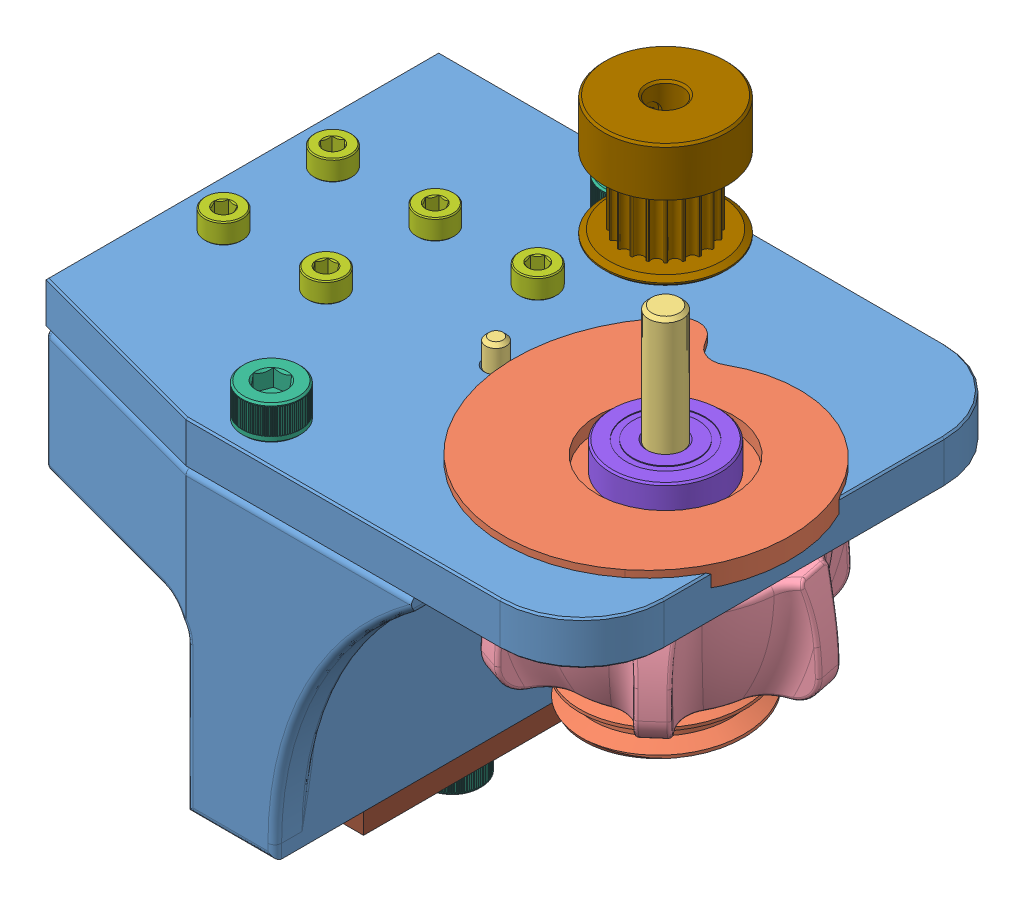
SolidWorks assembly x_axis_tensioner, configuration Default. Lengths in mm.
Overall size (96.3 104.85 65.88).
20 component instances, 11 part files, 39 mates.
Components (placement in the parent):
- x_axis_tensioner_mount-1: x_axis_tensioner_mount [Default] at (16.4131 58.7719 60.8954) size (86 49.95 65.29)
- bearing_can-1: bearing_can [Default] at (85.2345 53.1219 96.4954) x (0.83402 0 -0.551734) z (0.551734 0 0.83402) size (42 32.25 45.58)
- axel_pin-1: axel_pin [cam_follower] at (60.4131 76.7719 96.4954) x (0.730878 0 0.682508) z (-0.682508 0 0.730878) size (3 10 3)
- lock_nut-1: lock_nut [Default] at (85.2345 60.7719 96.4954) x (-0.946784 0 -0.321869) z (0 1 0) size (38.75 41.54 18.39)
- 94180A361_Tapered Heat-Set Inserts for Plastic-2: 94180A361_Tapered Heat-Set Inserts for Plastic [94180A361] at (50.9131 73.4069 119.8954) x (1 0 0) z (0 1 0) size (8.33 8.33 7.05)
- 94180A361_Tapered Heat-Set Inserts for Plastic-3: 94180A361_Tapered Heat-Set Inserts for Plastic [94180A361] at (50.9131 73.4069 67.1454) x (1 0 0) z (0 1 0) size (8.33 8.33 7.05)
- 91290A231_Alloy Steel Socket Head Screw-2: 91290A231_Alloy Steel Socket Head Screw [91290A231] at (50.9131 78.1219 67.1454) x (-0.865483 0 0.500939) z (0 1 0) size (8.5 8.5 20.34)
- 91290A231_Alloy Steel Socket Head Screw-3: 91290A231_Alloy Steel Socket Head Screw [91290A231] at (50.9131 78.1219 119.8954) x (0.769716 0 -0.638387) z (0 1 0) size (8.5 8.5 20.34)
- 91290A572_Black-Oxide Alloy Steel Socket Head Screw-3: 91290A572_Black-Oxide Alloy Steel Socket Head Screw [30] at (23.4131 69.6219 99.3954) x (0.088431 0 -0.996082) z (0 1 0) size (5.5 5.5 33.14)
- 91290A572_Black-Oxide Alloy Steel Socket Head Screw-4: 91290A572_Black-Oxide Alloy Steel Socket Head Screw [30] at (38.4131 69.6219 99.3954) x (0.924191 0 0.38193) z (0 1 0) size (5.5 5.5 33.14)
- 6153K69_Stainless Steel Ball Bearing-3: 6153K69_Stainless Steel Ball Bearing [6153K69] at (85.2345 83.6219 96.4954) x (0.992311 0 0.123769) z (0 -1 0) size (16 16 5)
- 6153K69_Stainless Steel Ball Bearing-4: 6153K69_Stainless Steel Ball Bearing [6153K69] at (85.2345 55.6219 96.4954) x (1 0 0) z (0 1 0) size (16 16 5)
- axel_pin-2: axel_pin [Default] at (85.2345 53.1219 96.4954) x (0.742128 0 0.670258) z (-0.670258 0 0.742128) size (5 50 5)
- 91290A572_Black-Oxide Alloy Steel Socket Head Screw-6: 91290A572_Black-Oxide Alloy Steel Socket Head Screw [30] at (23.4131 69.6219 83.3954) x (0.331356 0 0.943506) z (0 1 0) size (5.5 5.5 33.14)
- 91290A572_Black-Oxide Alloy Steel Socket Head Screw-7: 91290A572_Black-Oxide Alloy Steel Socket Head Screw [30] at (38.4131 69.6219 83.3954) x (-0.869185 0 -0.494488) z (0 1 0) size (5.5 5.5 33.14)
- 91290A572_Black-Oxide Alloy Steel Socket Head Screw-9: 91290A572_Black-Oxide Alloy Steel Socket Head Screw [30] at (53.4131 69.6219 83.3954) x (0.248464 0 -0.968641) z (0 1 0) size (5.5 5.5 33.14)
- 3684N13_Corrosion-Resistant HTD Timing Belt Pulley-1: 3684N13_Corrosion-Resistant HTD Timing Belt Pulley [3684N13] at (85.2345 122.2873 96.4954) x (0.002719 0 0.999996) z (0 -1 0) size (18 18 18)
- 94180A331_Tapered Heat-Set Inserts for Plastic-2: 94180A331_Tapered Heat-Set Inserts for Plastic [94180A331] at (50.9131 35.0719 93.3954) x (1 0 0) z (0 -1 0) size (5.56 5.56 3.99)
- belp_grip-1: belp_grip [Default] at (50.9131 30.1719 93.3954) x (0 0 1) z (-1 0 0) size (39 3 13)
- 91290A231_Alloy Steel Socket Head Screw-5: 91290A231_Alloy Steel Socket Head Screw [91290A231] at (50.9131 35.1719 93.3954) x (0.869544 0 -0.493855) z (0 -1 0) size (8.5 8.5 20.34)
Mates (geometry in assembly coordinates):
- Concentric3: concentric aligned: cylinder of x_axis_tensioner_mount-1 through (60.4131 83.1219 96.4954) axis (0 -1 0) radius 1.5; cylinder of axel_pin-1 through (60.4131 86.7719 96.4954) axis (0 -1 0) radius 1.5
- Coincident3: coincident anti-aligned: plane of x_axis_tensioner_mount-1 through (102.4131 76.7719 60.8954) normal (0 1 0); plane of axel_pin-1 through (60.4131 76.7719 96.4954) normal (0 -1 0)
- CamMateTangent1: cam tangent anti-aligned: cylinder of bearing_can-1 through (86.7843 86.1219 95.6577) axis (0 -1 0) radius 17.2459; cylinder of axel_pin-1 through (60.4131 86.7719 96.4954) axis (0 -1 0) radius 1.5
- Concentric51: concentric aligned: cylinder of x_axis_tensioner_mount-1 through (50.9131 64.7719 119.8954) axis (0 1 0) radius 3.25; cylinder of 94180A361_Tapered Heat-Set Inserts for Plastic-2 through (50.9131 76.7719 119.8954) axis (0 1 0) radius 4.165
- Coincident51: coincident aligned: plane of x_axis_tensioner_mount-1 through (102.4131 76.7719 60.8954) normal (0 1 0); plane of 94180A361_Tapered Heat-Set Inserts for Plastic-2 through (50.9131 76.7719 117.3954) normal (0 1 0)
- Concentric61: concentric aligned: cylinder of x_axis_tensioner_mount-1 through (50.9131 64.7719 67.1454) axis (0 1 0) radius 3.25; cylinder of 94180A361_Tapered Heat-Set Inserts for Plastic-3 through (50.9131 76.7719 67.1454) axis (0 1 0) radius 4.165
- Coincident61: coincident aligned: plane of x_axis_tensioner_mount-1 through (102.4131 76.7719 60.8954) normal (0 1 0); plane of 94180A361_Tapered Heat-Set Inserts for Plastic-3 through (50.9131 76.7719 64.6454) normal (0 1 0)
- Coincident71: coincident anti-aligned: plane of x_axis_tensioner_mount-1 through (16.4131 83.1219 125.8954) normal (0 1 0); plane of 91290A231_Alloy Steel Socket Head Screw-2 through (54.375 83.1219 65.1416) normal (0 -1 0)
- Coincident81: coincident anti-aligned: plane of x_axis_tensioner_mount-1 through (16.4131 83.1219 125.8954) normal (0 1 0); plane of 91290A231_Alloy Steel Socket Head Screw-3 through (47.8342 83.1219 122.4489) normal (0 -1 0)
- Coincident101: coincident anti-aligned: plane of x_axis_tensioner_mount-1 through (16.4131 83.1219 125.8954) normal (0 1 0); plane of 91290A572_Black-Oxide Alloy Steel Socket Head Screw-3 through (20.8233 83.1219 99.1654) normal (0 -1 0)
- Coincident111: coincident anti-aligned: plane of x_axis_tensioner_mount-1 through (16.4131 83.1219 125.8954) normal (0 1 0); plane of 91290A572_Black-Oxide Alloy Steel Socket Head Screw-4 through (39.4061 83.1219 96.9925) normal (0 -1 0)
- Concentric12: concentric aligned: cylinder of x_axis_tensioner_mount-1 through (38.4131 88.0716 99.3954) axis (0 -1 0) radius 1.75; cylinder of 91290A572_Black-Oxide Alloy Steel Socket Head Screw-4 through (38.4131 53.1219 99.3954) axis (0 -1 0) radius 1.5
- Concentric131: concentric anti-aligned: cylinder of bearing_can-1 through (85.2345 53.1219 96.4954) axis (0 -1 0) radius 4; cone of 6153K69_Stainless Steel Ball Bearing-3 through (85.2345 81.1219 96.4954) axis (0 1 0)
- Concentric141: concentric aligned: cylinder of bearing_can-1 through (85.2345 53.1219 96.4954) axis (0 -1 0) radius 4; cone of 6153K69_Stainless Steel Ball Bearing-4 through (85.2345 58.1219 96.4954) axis (0 -1 0)
- Coincident131: coincident anti-aligned: plane of bearing_can-1 through (83.0276 58.1219 93.1593) normal (0 -1 0); plane of 6153K69_Stainless Steel Ball Bearing-4 through (85.2345 58.1219 91.7289) normal (0 1 0)
- Concentric15: concentric aligned: cylinder of 6153K69_Stainless Steel Ball Bearing-3 through (85.2345 81.1219 96.4954) axis (0 -1 0) radius 2.5; cylinder of axel_pin-2 through (85.2345 103.1219 96.4954) axis (0 -1 0) radius 2.5
- Coincident14: coincident aligned: plane of 6153K69_Stainless Steel Ball Bearing-4 through (85.2345 53.1219 88.7454) normal (0 -1 0); plane of axel_pin-2 through (85.2345 53.1219 96.4954) normal (0 -1 0)
- Concentric17: concentric aligned: cylinder of x_axis_tensioner_mount-1 through (23.4131 88.0716 99.3954) axis (0 -1 0) radius 1.75; cylinder of 91290A572_Black-Oxide Alloy Steel Socket Head Screw-3 through (23.4131 53.1219 99.3954) axis (0 -1 0) radius 1.5
- Concentric142: concentric anti-aligned: circle of 94180A361_Tapered Heat-Set Inserts for Plastic-2; circle of 91290A231_Alloy Steel Socket Head Screw-3
- Concentric143: concentric anti-aligned: circle of 94180A361_Tapered Heat-Set Inserts for Plastic-3; circle of 91290A231_Alloy Steel Socket Head Screw-2
- Concentric1441: concentric aligned: cone of x_axis_tensioner_mount-1 through (23.4131 82.8719 83.3954) axis (0 -1 0); cylinder of 91290A572_Black-Oxide Alloy Steel Socket Head Screw-6 through (23.4131 53.1219 83.3954) axis (0 -1 0) radius 1.5
- Coincident1321: coincident anti-aligned: plane of x_axis_tensioner_mount-1 through (16.4131 83.1219 125.8954) normal (0 1 0); plane of 91290A572_Black-Oxide Alloy Steel Socket Head Screw-6 through (25.8662 83.1219 82.5338) normal (0 -1 0)
- Concentric1451: concentric aligned: cone of x_axis_tensioner_mount-1 through (38.4131 82.8719 83.3954) axis (0 -1 0); cylinder of 91290A572_Black-Oxide Alloy Steel Socket Head Screw-7 through (38.4131 53.1219 83.3954) axis (0 -1 0) radius 1.5
- Coincident1331: coincident anti-aligned: plane of x_axis_tensioner_mount-1 through (16.4131 83.1219 125.8954) normal (0 1 0); plane of 91290A572_Black-Oxide Alloy Steel Socket Head Screw-7 through (37.1274 83.1219 85.6552) normal (0 -1 0)
- Concentric1461: concentric aligned: cone of x_axis_tensioner_mount-1 through (53.4131 82.8719 83.3954) axis (0 -1 0); cylinder of 91290A572_Black-Oxide Alloy Steel Socket Head Screw-9 through (53.4131 53.1219 83.3954) axis (0 -1 0) radius 1.5
- Coincident1341: coincident anti-aligned: plane of x_axis_tensioner_mount-1 through (16.4131 83.1219 125.8954) normal (0 1 0); plane of 91290A572_Black-Oxide Alloy Steel Socket Head Screw-9 through (50.8946 83.1219 82.7494) normal (0 -1 0)
- Coincident135: coincident anti-aligned: plane of x_axis_tensioner_mount-1 through (102.4131 76.7719 60.8954) normal (0 -1 0); plane of lock_nut-1 through (85.2345 76.7719 96.4954) normal (0 1 0)
- Coincident136: coincident anti-aligned: plane of bearing_can-1 through (85.2345 81.1219 96.4954) normal (0 1 0); plane of 6153K69_Stainless Steel Ball Bearing-3 through (84.2753 81.1219 104.1858) normal (0 -1 0)
- Slot1: slot anti-aligned: cylinder of bearing_can-1 through (85.2345 53.1219 96.4954) axis (0 -1 0) radius 12; cylinder of x_axis_tensioner_mount-1 through (77.4131 33.1719 96.4954) axis (0 1 0) radius 12.5; cylinder of x_axis_tensioner_mount-1 through (85.4131 33.1719 96.4954) axis (0 1 0) radius 12.5
- Coincident137: coincident anti-aligned: plane of x_axis_tensioner_mount-1 through (16.4131 83.1219 125.8954) normal (0 1 0); plane of bearing_can-1 through (86.9751 83.1219 95.3439) normal (0 -1 0)
- Concentric149: concentric aligned: cylinder of bearing_can-1 through (85.2345 53.1219 96.4954) axis (0 -1 0) radius 12; circle of lock_nut-1
- Concentric1462: concentric aligned: cylinder of axel_pin-2 through (85.2345 103.1219 96.4954) axis (0 -1 0) radius 2.5; cylinder of 3684N13_Corrosion-Resistant HTD Timing Belt Pulley-1 through (85.2345 111.7873 96.4954) axis (0 -1 0) radius 2.5
- Concentric14631: concentric aligned: cylinder of x_axis_tensioner_mount-1 through (50.9131 39.1719 93.3954) axis (0 -1 0) radius 2; cylinder of 94180A331_Tapered Heat-Set Inserts for Plastic-2 through (50.9131 33.1719 93.3954) axis (0 -1 0) radius 2.78
- Coincident13421: coincident aligned: plane of x_axis_tensioner_mount-1 through (57.4131 33.1719 125.8954) normal (0 -1 0); plane of 94180A331_Tapered Heat-Set Inserts for Plastic-2 through (50.9131 33.1719 94.8954) normal (0 -1 0)
- Coincident1343: coincident aligned: plane of x_axis_tensioner_mount-1 through (44.4131 33.1719 125.8954) normal (-1 0 0); plane of belp_grip-1 through (44.4131 33.1719 93.3954) normal (-1 0 0)
- Coincident1344: coincident anti-aligned: plane of x_axis_tensioner_mount-1 through (57.4131 33.1719 125.8954) normal (0 -1 0); plane of belp_grip-1 through (50.9131 33.1719 93.3954) normal (0 1 0)
- Concentric1464: concentric aligned: circle of 94180A331_Tapered Heat-Set Inserts for Plastic-2; circle of belp_grip-1
- Concentric14651: concentric anti-aligned: cylinder of belp_grip-1 through (50.9131 33.1719 93.3954) axis (0 -1 0) radius 1.65; cone of 91290A231_Alloy Steel Socket Head Screw-5 through (50.9131 30.1719 93.3954) axis (0 1 0)
- Coincident13451: coincident anti-aligned: plane of belp_grip-1 through (50.9131 30.1719 93.3954) normal (0 -1 0); plane of 91290A231_Alloy Steel Socket Head Screw-5 through (47.4349 30.1719 95.3708) normal (0 1 0)
